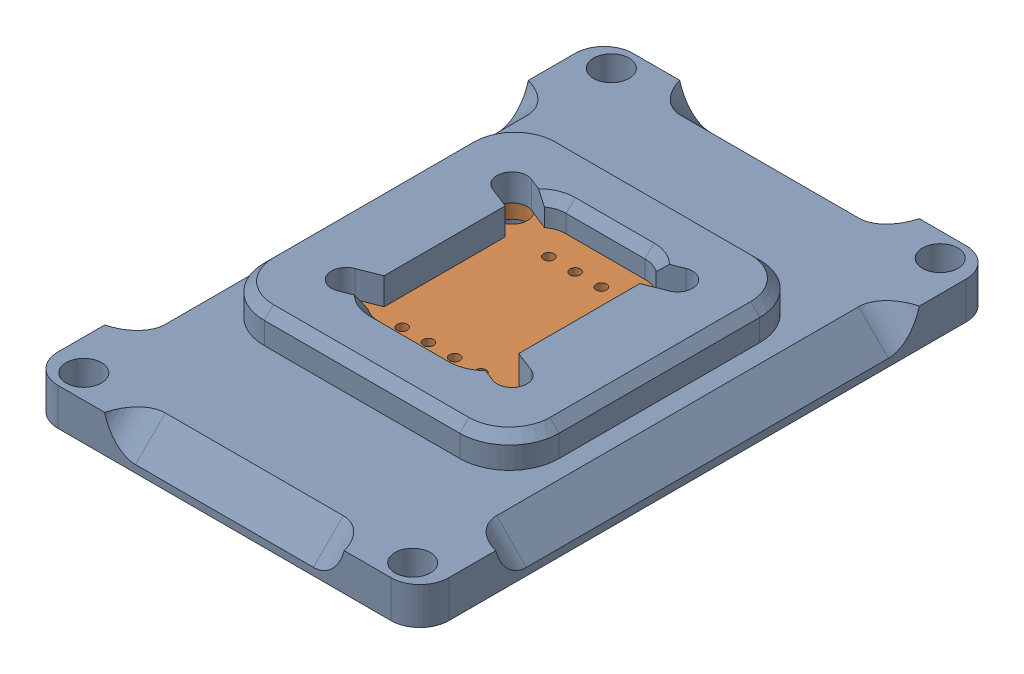
SolidWorks assembly Encoder_6__1, configuration Default. Lengths in mm.
Overall size (37.8 6.6 55.6).
2 component instances, 2 part files, 0 mates.
Components (placement in the parent):
- EncoderHousing_1-1: EncoderHousing_1 [Default] at (0 -482.7 790) x (1 0 0) z (0 -1 0) size (37.8 55.6 6.6)
- AS5600_1-1: AS5600_1 [Default] at (0 -480.4 790) x (1 0 0) z (0 0 -1) size (23 3.5 23)
